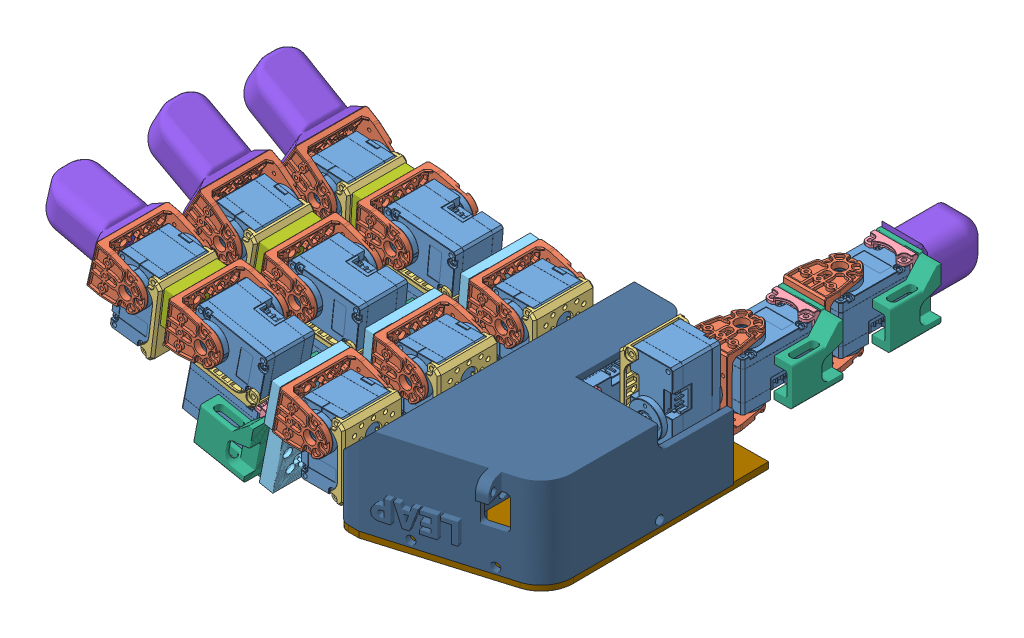
SolidWorks assembly assembly, configuration Default. Lengths in mm.
Overall size (232.03 87.75 239.65).
60 component instances, 10 part files, 172 mates.
Components (placement in the parent):
- XL,XC-330-1: XL,XC-330 [Default] at (75.5947 17.4182 -95.0965) size (20 34 29.02)
- fpx330-h101-1: fpx330-h101 [Default] at (61.8511 20.0849 -103.0965) x (-0.190479 -0.981691 0) z (0 0 -1) size (20 25 34.6)
- fpx330-s101-1: fpx330-s101 [Default] at (85.5947 9.9182 -103.0965) x (0 -1 0) z (0 0 1) size (34 7 28.6)
- fpx330-s102-1: fpx330-s102 [Default] at (42.4707 -3.1489 -103.0965) x (0 0 1) z (0.190479 0.981691 0) size (20 7 28.6)
- XL,XC-330-2: XL,XC-330 [Default] at (34.6684 6.5142 -103.0965) x (0 0 1) z (0.190479 0.981691 0) size (20 34 29.02)
- mcp_bracket-1: mcp_bracket [Default] at (58.9719 20.9961 -103.2814) x (0.190479 0.981691 0) z (0 0 1) size (53 6.5 33)
- cable_spacer-1: cable_spacer [Default] at (44.3361 -20.3094 -112.1175) x (0 0 1) z (-0.190479 -0.981691 0) size (28.5 24.1 27.99)
- fpx330-s101-2: fpx330-s101 [Default] at (29.1153 17.2689 -103.0965) x (0.981691 -0.190479 0) z (0 0 -1) size (34 7 28.6)
- XL,XC-330-3: XL,XC-330 [Default] at (23.6574 28.5144 -95.0965) x (0.190479 0.981691 0) z (0 0 1) size (20 34 29.02)
- fpx330-h101-2: fpx330-h101 [Default] at (9.7688 30.2768 -103.0965) x (-0.125885 -0.992045 0) z (0 0 -1) size (20 25 34.6)
- dip_spacer-1: dip_spacer [Default] at (1.6224 38.3666 -86.5965) x (-0.125885 -0.992045 0) z (0 0 1) size (16 6.1 25)
- XL,XC-330-4: XL,XC-330 [Default] at (-12.1554 33.0588 -95.0965) x (0.992045 -0.125885 0) z (0 0 1) size (20 34 29.02)
- fpx330-s101-3: fpx330-s101 [Default] at (-3.1791 24.3596 -103.0965) x (-0.125885 -0.992045 0) z (0 0 1) size (34 7 28.6)
- fpx330-h101-4: fpx330-h101 [Default] at (-25.8012 36.1882 -103.0965) x (-0.22353 -0.974697 0) z (0 0 -1) size (20 25 34.6)
- finger_tip-1: finger_tip [Default] at (-30.8488 27.5992 -86.5965) x (0.22353 0.974697 0) z (0 0 1) size (20.6 32.5 33)
- finger_tip-3: finger_tip [Default] at (-32.0995 30.1289 -131.9559) x (0.477322 0.878721 0.003661) z (0 -0.004166 0.999991) size (20.6 32.5 33)
- XL,XC-330-9: XL,XC-330 [Default] at (-12.6266 30.3978 -140.4549) x (0.983896 -0.17874 -0.000745) z (0 -0.004166 0.999991) size (20 34 29.02)
- dip_spacer-3: dip_spacer [Default] at (1.4153 34.9259 -131.9359) x (-0.178742 -0.983888 -0.004099) z (0 -0.004166 0.999991) size (16 6.1 25)
- fpx330-h101-8: fpx330-h101 [Default] at (-24.9288 37.1135 -148.427) x (-0.477322 -0.878721 -0.003661) z (0 0.004166 -0.999991) size (20 25 34.6)
- fpx330-s101-7: fpx330-s101 [Default] at (-4.1282 21.2645 -148.493) x (-0.178742 -0.983888 -0.004099) z (0 -0.004166 0.999991) size (34 7 28.6)
- XL,XC-330-10: XL,XC-330 [Default] at (22.8921 23.9453 -140.4818) x (0.104821 0.994482 0.004143) z (0 -0.004166 0.999991) size (20 34 29.02)
- fpx330-h101-9: fpx330-h101 [Default] at (61.6719 18.8856 -148.5029) x (-0.104821 -0.994482 -0.004143) z (0 0.004166 -0.999991) size (20 25 34.6)
- cable_spacer-3: cable_spacer [Default] at (47.7178 -22.8348 -157.6978) x (0 -0.004166 0.999991) z (-0.104821 -0.994482 -0.004143) size (28.5 24.1 27.99)
- mcp_bracket-4: mcp_bracket [Default] at (58.7247 19.545 -148.6851) x (0.104821 0.994482 0.004143) z (0 -0.004166 0.999991) size (53 6.5 33)
- XL,XC-330-11: XL,XC-330 [Default] at (35.7654 3.0139 -148.569) x (0 -0.004166 0.999991) z (0.104821 0.994482 0.004143) size (20 34 29.02)
- XL,XC-330-12: XL,XC-330 [Default] at (75.5947 17.3848 -140.5091) x (1 0 0) z (0 -0.004166 0.999991) size (20 34 29.02)
- fpx330-s102-6: fpx330-s102 [Default] at (44.3745 -5.9378 -148.6063) x (0 -0.004166 0.999991) z (0.104821 0.994482 0.004143) size (20 7 28.6)
- fpx330-s101-8: fpx330-s101 [Default] at (85.5947 9.9182 -148.5403) x (0 -0.999991 -0.004166) z (0 -0.004166 0.999991) size (34 7 28.6)
- fpx330-s101-9: fpx330-s101 [Default] at (29.3025 13.2476 -148.5264) x (0.994491 -0.10482 -0.000437) z (0 0.004166 -0.999991) size (34 7 28.6)
- fpx330-h101-10: fpx330-h101 [Default] at (9.1175 26.4809 -148.4713) x (-0.178742 -0.983888 -0.004099) z (0 0.004166 -0.999991) size (20 25 34.6)
- finger_tip-4: finger_tip [Default] at (-32.7116 25.6013 -177.4965) x (0.504165 0.863607 0) z (0 0 1) size (20.6 32.5 33)
- XL,XC-330-13: XL,XC-330 [Default] at (-13.2407 25.2347 -185.9965) x (0.998439 -0.05586 0) z (0 0 1) size (20 34 29.02)
- dip_spacer-4: dip_spacer [Default] at (0.1301 31.4976 -177.4965) x (-0.05586 -0.998439 0) z (0 0 1) size (16 6.1 25)
- fpx330-h101-11: fpx330-h101 [Default] at (-25.3312 32.293 -193.9965) x (-0.504165 -0.863607 0) z (0 0 -1) size (20 25 34.6)
- fpx330-s101-10: fpx330-s101 [Default] at (-3.6752 17.1878 -193.9965) x (-0.05586 -0.998439 0) z (0 0 1) size (34 7 28.6)
- XL,XC-330-14: XL,XC-330 [Default] at (22.803 23.2182 -185.9965) x (0.090472 0.995899 0) z (0 0 1) size (20 34 29.02)
- fpx330-h101-12: fpx330-h101 [Default] at (61.6521 18.6848 -193.9965) x (-0.090472 -0.995899 0) z (0 0 -1) size (20 25 34.6)
- cable_spacer-4: cable_spacer [Default] at (48.3016 -23.2704 -203.0175) x (0 0 1) z (-0.090472 -0.995899 0) size (28.5 24.1 27.99)
- mcp_bracket-5: mcp_bracket [Default] at (58.6958 19.3009 -194.1814) x (0.090472 0.995899 0) z (0 0 1) size (53 6.5 33)
- XL,XC-330-15: XL,XC-330 [Default] at (35.9772 2.4411 -193.9965) x (0 0 1) z (0.090472 0.995899 0) size (20 34 29.02)
- XL,XC-330-16: XL,XC-330 [Default] at (75.5947 17.4182 -185.9965) size (20 34 29.02)
- fpx330-s102-7: fpx330-s102 [Default] at (44.7145 -6.3856 -193.9965) x (0 0 1) z (0.090472 0.995899 0) size (20 7 28.6)
- fpx330-s101-11: fpx330-s101 [Default] at (85.5947 9.9182 -193.9965) x (0 -1 0) z (0 0 1) size (34 7 28.6)
- fpx330-s101-12: fpx330-s101 [Default] at (29.3675 12.5806 -193.9965) x (0.995899 -0.090472 0) z (0 0 -1) size (34 7 28.6)
- fpx330-h101-13: fpx330-h101 [Default] at (8.8248 24.0002 -193.9965) x (-0.05586 -0.998439 0) z (0 0 -1) size (20 25 34.6)
- palm_upper_no_holes-1: palm_upper_no_holes [Default] at (77.2088 -9.5217 -112.2357) x (-0.999969 -0.001716 0.007697) z (0.007698 -0.00047 0.99997) size (80 10 125)
- palm_lower-1: palm_lower [Default] at (77.3429 33.4085 -112.2687) x (-1 -0.000863 0.000028) z (0.000028 0 1) size (80.01 43 125.73)
- fpx330-s102-8: fpx330-s102 [Default] at (150.9978 20.1559 -240.0161) x (0.999999 0.000861 -0.000917) z (-0.000863 0.999996 -0.002588) size (20 7 28.6)
- cable_spacer-5: cable_spacer [Default] at (141.9863 3.644 -245.0652) x (0.999999 0.000861 -0.000917) z (0.000863 -0.999996 0.002588) size (28.5 24.1 27.99)
- finger_tip-5: finger_tip [Default] at (160.2884 3.3945 -291.6814) x (-0.999963 0.008517 0.000893) z (-0.008515 -0.99996 0.002597) size (20.6 32.5 33)
- fpx330-s102-9: fpx330-s102 [Default] at (123.5714 20.3407 -159.4912) x (-0.000863 0.999996 -0.002588) z (0.999999 0.000861 -0.000917) size (20 7 28.6)
- XL,XC-330-22: XL,XC-330 [Default] at (115.549 20.2704 -183.9838) x (-0.000863 0.999996 -0.002588) z (-0.999999 -0.000861 0.000917) size (20 34 29.02)
- fpx330-s101-16: fpx330-s101 [Default] at (141.0425 27.7923 -184.0266) x (-0.000863 0.999996 -0.002588) z (0.000915 0.002589 0.999996) size (34 7 28.6)
- XL,XC-330-23: XL,XC-330 [Default] at (151.0417 20.2802 -192.0163) x (0.999999 0.000861 -0.000917) z (-0.000915 -0.002589 -0.999996) size (20 34 29.02)
- fpx330-h101-17: fpx330-h101 [Default] at (151.033 20.2556 -201.5163) x (-0.999999 -0.000861 0.000917) z (-0.000863 0.999996 -0.002588) size (20 25 34.6)
- XL,XC-330-25: XL,XC-330 [Default] at (151.0133 28.2194 -215.5369) x (-0.999999 -0.000861 0.000917) z (-0.000863 0.999996 -0.002588) size (20 34 29.02)
- fpx330-h101-18: fpx330-h101 [Default] at (150.9904 20.135 -248.1161) x (-0.999999 -0.000861 0.000917) z (-0.000863 0.999996 -0.002588) size (20 25 34.6)
- XL,XC-330-26: XL,XC-330 [Default] at (150.9707 28.0987 -262.1368) x (-0.999999 -0.000861 0.000917) z (-0.000863 0.999996 -0.002588) size (20 34 29.02)
- fpx330-s102-12: fpx330-s102 [Default] at (150.9552 20.0353 -286.616) x (0.999999 0.000861 -0.000917) z (-0.000863 0.999996 -0.002588) size (20 7 28.6)
- cable_spacer-8: cable_spacer [Default] at (141.9437 3.5233 -291.665) x (0.999999 0.000861 -0.000917) z (0.000863 -0.999996 0.002588) size (28.5 24.1 27.99)
Mates (geometry in assembly coordinates):
- 同心12: concentric anti-aligned: cylinder of XL,XC-330-1 through (83.5947 -5.0818 -110.0965) axis (0 0 1) radius 1; circle of fpx330-s101-1
- 同心13: concentric aligned: cylinder of XL,XC-330-1 through (83.5947 24.9182 -110.0965) axis (0 0 1) radius 1; cylinder of fpx330-s101-1 through (83.5947 24.9182 -117.3965) axis (0 0 1) radius 1.025
- 重合9: coincident anti-aligned: plane of XL,XC-330-1 through (75.5947 17.4182 -114.5965) normal (0 0 -1); plane of fpx330-s101-1 through (85.5947 9.9182 -114.5965) normal (0 0 1)
- 同心23: concentric anti-aligned: cylinder of fpx330-s102-1 through (43.2311 11.2703 -95.0965) axis (0.190479 0.981691 0) radius 1.025; cylinder of XL,XC-330-2 through (42.0311 5.0856 -95.0965) axis (-0.190479 -0.981691 0) radius 1
- 重合12: coincident anti-aligned: plane of fpx330-s102-1 through (44.6612 8.1406 -103.0965) normal (-0.190479 -0.981691 0); plane of XL,XC-330-2 through (35.3351 9.9501 -103.0965) normal (0.190479 0.981691 0)
- 同心24: concentric aligned: cylinder of fpx330-s102-1 through (37.7834 -16.8061 -111.0965) axis (0.190479 0.981691 0) radius 1.025; cylinder of XL,XC-330-2 through (39.1739 -9.6398 -111.0965) axis (0.190479 0.981691 0) radius 1
- 重合15: coincident anti-aligned: plane of XL,XC-330-1 through (75.5947 17.4182 -88.5965) normal (0 0 1); plane of fpx330-h101-1 through (61.8511 20.0849 -88.5965) normal (0 0 -1)
- 同心26: concentric anti-aligned: cylinder of XL,XC-330-1 through (75.5947 17.4182 -88.5965) axis (0 0 1) radius 2.8; cylinder of fpx330-h101-1 through (75.5947 17.4182 -85.7965) axis (0 0 -1) radius 3
- 平行1: parallel anti-aligned: plane of fpx330-h101-1 through (58.906 20.6564 -103.0965) normal (-0.981691 0.190479 0); plane of mcp_bracket-1 through (51.052 -19.8214 -102.0669) normal (0.981691 -0.190479 0)
- 同心28: concentric aligned: cylinder of fpx330-h101-1 through (57.7631 14.7662 -103.0965) axis (-0.981691 0.190479 0) radius 1.025; cylinder of mcp_bracket-1 through (57.7631 14.7662 -103.0965) axis (-0.981691 0.190479 0) radius 1.2734
- 同心29: concentric anti-aligned: cylinder of fpx330-h101-1 through (60.0489 26.5465 -103.0965) axis (-0.981691 0.190479 0) radius 1.025; cylinder of mcp_bracket-1 through (58.5763 26.8322 -103.0965) axis (0.981691 -0.190479 0) radius 1.2734
- 重合17: coincident anti-aligned: plane of fpx330-h101-1 through (58.906 20.6564 -103.0965) normal (-0.981691 0.190479 0); plane of mcp_bracket-1 through (51.052 -19.8214 -102.0669) normal (0.981691 -0.190479 0)
- 同心31: concentric anti-aligned: cylinder of fpx330-s102-1 through (46.5586 2.1698 -103.0965) axis (0.981691 -0.190479 0) radius 1.025; circle of cable_spacer-1
- 同心32: concentric anti-aligned: cylinder of fpx330-s102-1 through (44.2728 -9.6105 -103.0965) axis (0.981691 -0.190479 0) radius 1.025; circle of cable_spacer-1
- 重合30: coincident anti-aligned: plane of fpx330-s102-1 through (45.4157 -3.7203 -103.0965) normal (0.981691 -0.190479 0); plane of cable_spacer-1 through (47.8473 8.8114 -104.0783) normal (-0.981691 0.190479 0)
- 同心33: concentric aligned: circle of mcp_bracket-1; circle of cable_spacer-1
- 同心34: concentric aligned: circle of mcp_bracket-1; circle of cable_spacer-1
- 重合35: coincident anti-aligned: plane of mcp_bracket-1 through (47.1511 -5.8015 -112.2192) normal (-0.981691 0.190479 0); plane of cable_spacer-1 through (49.9088 8.4114 -102.1568) normal (0.981691 -0.190479 0)
- 同心35: concentric aligned: cylinder of fpx330-s101-2 through (44.2216 16.3751 -88.7965) axis (0 0 -1) radius 1.025; cylinder of XL,XC-330-3 through (44.2216 16.3751 -95.0965) axis (0 0 -1) radius 1
- 同心36: concentric aligned: circle of fpx330-s101-2; cylinder of XL,XC-330-3 through (14.7709 22.0894 -95.0965) axis (0 0 -1) radius 1
- 重合36: coincident anti-aligned: plane of fpx330-s101-2 through (29.1153 17.2689 -91.5965) normal (0 0 -1); plane of XL,XC-330-3 through (23.6574 28.5144 -91.5965) normal (0 0 1)
- 同心38: concentric anti-aligned: cylinder of XL,XC-330-3 through (23.6574 28.5144 -88.5965) axis (0 0 1) radius 2.8; cylinder of fpx330-h101-2 through (23.6574 28.5144 -85.7965) axis (0 0 -1) radius 3
- 重合38: coincident anti-aligned: plane of XL,XC-330-3 through (23.6574 28.5144 -88.5965) normal (0 0 1); plane of fpx330-h101-2 through (9.7688 30.2768 -88.5965) normal (0 0 -1)
- 同心40: concentric anti-aligned: cylinder of fpx330-h101-2 through (6.7926 30.6544 -109.0965) axis (-0.992045 0.125885 0) radius 1.025; circle of dip_spacer-1
- 同心41: concentric anti-aligned: cylinder of fpx330-h101-2 through (6.7926 30.6544 -97.0965) axis (-0.992045 0.125885 0) radius 1.025; circle of dip_spacer-1
- 重合40: coincident anti-aligned: plane of fpx330-h101-2 through (6.7926 30.6544 -103.0965) normal (-0.992045 0.125885 0); plane of dip_spacer-1 through (5.9978 24.3905 -110.5314) normal (0.992045 -0.125885 0)
- 同心42: concentric anti-aligned: cylinder of XL,XC-330-4 through (-7.0515 9.7307 -95.0965) axis (0 0 -1) radius 1; cylinder of fpx330-s101-3 through (-7.0515 9.7307 -88.7965) axis (0 0 1) radius 1.025
- 同心43: concentric anti-aligned: cylinder of XL,XC-330-4 through (-3.2749 39.4921 -95.0965) axis (0 0 -1) radius 1; cylinder of fpx330-s101-3 through (-3.2749 39.4921 -88.7965) axis (0 0 1) radius 1.025
- 重合41: coincident anti-aligned: plane of XL,XC-330-4 through (-12.1554 33.0588 -114.5965) normal (0 0 -1); plane of fpx330-s101-3 through (-3.1791 24.3596 -114.5965) normal (0 0 1)
- 同心44: concentric anti-aligned: circle of dip_spacer-1; circle of fpx330-s101-3
- 同心45: concentric aligned: circle of dip_spacer-1; cylinder of fpx330-s101-3 through (0.7412 31.4223 -97.0965) axis (0.992045 -0.125885 0) radius 1.025
- 重合42: coincident anti-aligned: plane of dip_spacer-1 through (-0.0537 25.1584 -95.6617) normal (-0.992045 0.125885 0); plane of fpx330-s101-3 through (-0.203 23.982 -103.0965) normal (0.992045 -0.125885 0)
- 重合48: coincident anti-aligned: plane of XL,XC-330-4 through (-12.1554 33.0588 -88.5965) normal (0 0 1); plane of fpx330-h101-4 through (-25.8012 36.1882 -88.5965) normal (0 0 -1)
- 同心47: concentric anti-aligned: circle of XL,XC-330-4; cylinder of fpx330-h101-4 through (-12.1554 33.0588 -85.7965) axis (0 0 -1) radius 3
- 同心48: concentric aligned: circle of fpx330-h101-4; circle of finger_tip-1
- 同心49: concentric aligned: circle of fpx330-h101-4; circle of finger_tip-1
- 重合49: coincident anti-aligned: plane of fpx330-h101-4 through (-28.7253 36.8588 -103.0965) normal (-0.974697 0.22353 0); plane of finger_tip-1 through (-30.32 29.9052 -112.0355) normal (0.974697 -0.22353 0)
- 同心50: concentric anti-aligned: circle of XL,XC-330-2; circle of fpx330-s101-2
- 同心51: concentric anti-aligned: circle of XL,XC-330-2; circle of fpx330-s101-2
- 重合50: coincident anti-aligned: plane of XL,XC-330-2 through (35.9065 12.8952 -103.0965) normal (0.190479 0.981691 0); plane of fpx330-s101-2 through (28.5439 14.3238 -103.0965) normal (-0.190479 -0.981691 0)
- 重合65: coincident anti-aligned: plane of XL,XC-330-9 through (-12.6266 30.479 -159.9547) normal (0 0.004166 -0.999991); plane of fpx330-s101-7 through (-4.1282 21.3125 -159.9929) normal (0 -0.004166 0.999991)
- 重合66: coincident anti-aligned: plane of cable_spacer-3 through (50.7845 6.2188 -147.6159) normal (0.994491 -0.10482 -0.000437); plane of mcp_bracket-4 through (49.2669 -8.1374 -157.7383) normal (-0.994491 0.10482 0.000437)
- 重合67: coincident anti-aligned: plane of XL,XC-330-10 through (22.8921 23.9182 -133.9818) normal (0 -0.004166 0.999991); plane of fpx330-h101-10 through (9.1175 26.4205 -133.9714) normal (0 0.004166 -0.999991)
- 重合68: coincident anti-aligned: plane of cable_spacer-3 through (48.6961 6.4469 -149.5366) normal (-0.994491 0.10482 0.000437); plane of fpx330-s102-6 through (47.358 -6.2522 -148.6077) normal (0.994491 -0.10482 -0.000437)
- 重合69: coincident anti-aligned: plane of dip_spacer-3 through (-0.9645 21.8641 -141.0556) normal (-0.983896 0.17874 0.000745); plane of fpx330-s101-7 through (-1.1765 20.7283 -148.4952) normal (0.983896 -0.17874 -0.000745)
- 重合70: coincident anti-aligned: plane of XL,XC-330-11 through (36.1323 6.4946 -148.5545) normal (0.104821 0.994482 0.004143); plane of fpx330-s102-6 through (45.58 5.4988 -148.5587) normal (-0.104821 -0.994482 -0.004143)
- 平行15: parallel anti-aligned: plane of fpx330-h101-9 through (58.6884 19.2001 -148.5016) normal (-0.994491 0.10482 0.000437); plane of mcp_bracket-4 through (54.3663 -21.8094 -147.6428) normal (0.994491 -0.10482 -0.000437)
- 重合71: coincident anti-aligned: plane of fpx330-h101-9 through (58.6884 19.2001 -148.5016) normal (-0.994491 0.10482 0.000437); plane of mcp_bracket-4 through (54.3663 -21.8094 -147.6428) normal (0.994491 -0.10482 -0.000437)
- 重合72: coincident anti-aligned: plane of XL,XC-330-12 through (75.5947 17.4661 -160.0089) normal (0 0.004166 -0.999991); plane of fpx330-s101-8 through (85.5947 9.9661 -160.0402) normal (0 -0.004166 0.999991)
- 重合73: coincident anti-aligned: plane of fpx330-h101-9 through (61.6719 18.8252 -134.003) normal (0 0.004166 -0.999991); plane of XL,XC-330-12 through (75.5947 17.3577 -134.0092) normal (0 -0.004166 0.999991)
- 同心77: concentric anti-aligned: cylinder of XL,XC-330-12 through (83.5947 -5.0525 -155.6027) axis (0 -0.004166 0.999991) radius 1; circle of fpx330-s101-8
- 同心78: concentric anti-aligned: cylinder of fpx330-h101-9 through (59.3173 25.167 -148.4767) axis (-0.994491 0.10482 0.000437) radius 1.025; cylinder of mcp_bracket-4 through (57.8256 25.3242 -148.4761) axis (0.994491 -0.10482 -0.000437) radius 1.2734
- 同心79: concentric aligned: cylinder of fpx330-h101-9 through (58.0595 13.2332 -148.5265) axis (-0.994491 0.10482 0.000437) radius 1.025; cylinder of mcp_bracket-4 through (58.0595 13.2332 -148.5265) axis (-0.994491 0.10482 0.000437) radius 1.2734
- 同心80: concentric anti-aligned: cylinder of XL,XC-330-11 through (43.2241 2.1944 -140.5724) axis (-0.104821 -0.994482 -0.004143) radius 1; cylinder of fpx330-s102-6 through (43.8845 8.4596 -140.5463) axis (0.104821 0.994482 0.004143) radius 1.025
- 同心81: concentric aligned: cylinder of XL,XC-330-11 through (41.6518 -12.6562 -156.6344) axis (0.104821 0.994482 0.004143) radius 1; cylinder of fpx330-s102-6 through (40.8866 -19.9159 -156.6646) axis (0.104821 0.994482 0.004143) radius 1.025
- 同心82: concentric anti-aligned: cylinder of fpx330-h101-9 through (75.5947 17.3461 -131.2092) axis (0 0.004166 -0.999991) radius 3; cylinder of XL,XC-330-12 through (75.5947 17.3577 -134.0092) axis (0 -0.004166 0.999991) radius 2.8
- 同心83: concentric aligned: cylinder of XL,XC-330-12 through (83.5947 24.9472 -155.4777) axis (0 -0.004166 0.999991) radius 1; cylinder of fpx330-s101-8 through (83.5947 24.9777 -162.7777) axis (0 -0.004166 0.999991) radius 1.025
- 重合74: coincident anti-aligned: plane of XL,XC-330-10 through (22.8921 23.9307 -136.9818) normal (0 -0.004166 0.999991); plane of fpx330-s101-9 through (29.3025 13.1997 -137.0265) normal (0 0.004166 -0.999991)
- 重合75: coincident anti-aligned: plane of dip_spacer-3 through (5.0372 20.8358 -155.9297) normal (0.983896 -0.17874 -0.000745); plane of fpx330-h101-10 through (6.1658 27.0172 -148.469) normal (-0.983896 0.17874 0.000745)
- 同心84: concentric anti-aligned: cylinder of XL,XC-330-10 through (22.8921 23.9182 -133.9818) axis (0 -0.004166 0.999991) radius 2.8; cylinder of fpx330-h101-10 through (22.8921 23.9065 -131.1818) axis (0 0.004166 -0.999991) radius 3
- 同心85: concentric anti-aligned: circle of dip_spacer-3; circle of fpx330-s101-7
- 同心86: concentric anti-aligned: circle of dip_spacer-3; cylinder of fpx330-h101-10 through (6.1658 27.0422 -154.469) axis (-0.983896 0.17874 0.000745) radius 1.025
- 同心87: concentric aligned: cylinder of XL,XC-330-10 through (44.4296 13.6309 -140.5247) axis (0 0.004166 -0.999991) radius 1; cylinder of fpx330-s101-9 through (44.4296 13.6047 -134.2248) axis (0 0.004166 -0.999991) radius 1.025
- 同心88: concentric aligned: cylinder of XL,XC-330-10 through (14.5948 16.7755 -140.5116) axis (0 0.004166 -0.999991) radius 1; circle of fpx330-s101-9
- 同心89: concentric anti-aligned: circle of dip_spacer-3; cylinder of fpx330-h101-10 through (6.1658 26.9922 -142.4691) axis (-0.983896 0.17874 0.000745) radius 1.025
- 同心90: concentric anti-aligned: cylinder of XL,XC-330-9 through (-8.7771 6.8304 -140.5531) axis (0 0.004166 -0.999991) radius 1; cylinder of fpx330-s101-7 through (-8.7771 6.8041 -134.2531) axis (0 -0.004166 0.999991) radius 1.025
- 同心91: concentric anti-aligned: cylinder of XL,XC-330-9 through (-3.4148 36.347 -140.4301) axis (0 0.004166 -0.999991) radius 1; cylinder of fpx330-s101-7 through (-3.4148 36.3208 -134.1302) axis (0 -0.004166 0.999991) radius 1.025
- 同心92: concentric aligned: circle of dip_spacer-3; cylinder of fpx330-s101-7 through (0.1641 28.0825 -142.4645) axis (0.983896 -0.17874 -0.000745) radius 1.025
- 同心93: concentric anti-aligned: circle of XL,XC-330-9; cylinder of fpx330-h101-8 through (-12.6266 30.359 -131.155) axis (0 0.004166 -0.999991) radius 3
- 同心94: concentric aligned: circle of cable_spacer-3; circle of mcp_bracket-4
- 同心95: concentric aligned: circle of cable_spacer-3; circle of mcp_bracket-4
- 同心96: concentric anti-aligned: circle of cable_spacer-3; cylinder of fpx330-s102-6 through (46.7291 -12.2191 -148.6325) axis (0.994491 -0.10482 -0.000437) radius 1.025
- 同心97: concentric anti-aligned: circle of cable_spacer-3; cylinder of fpx330-s102-6 through (47.9869 -0.2853 -148.5828) axis (0.994491 -0.10482 -0.000437) radius 1.025
- 重合76: coincident anti-aligned: plane of XL,XC-330-9 through (-12.6266 30.3707 -133.9549) normal (0 -0.004166 0.999991); plane of fpx330-h101-8 through (-24.9288 37.0531 -133.9271) normal (0 0.004166 -0.999991)
- 重合77: coincident anti-aligned: plane of finger_tip-3 through (-30.9702 32.3138 -157.386) normal (0.878729 -0.477317 -0.001989); plane of fpx330-h101-8 through (-27.565 38.5455 -148.421) normal (-0.878729 0.477317 0.001989)
- 同心98: concentric anti-aligned: circle of XL,XC-330-11; circle of fpx330-s101-9
- 同心99: concentric aligned: circle of finger_tip-3; circle of fpx330-h101-8
- 同心100: concentric anti-aligned: circle of XL,XC-330-11; circle of fpx330-s101-9
- 同心101: concentric aligned: circle of finger_tip-3; circle of fpx330-h101-8
- 重合78: coincident anti-aligned: plane of XL,XC-330-11 through (36.4468 9.478 -148.5421) normal (0.104821 0.994482 0.004143); plane of fpx330-s101-9 through (28.9881 10.2642 -148.5388) normal (-0.104821 -0.994482 -0.004143)
- 重合79: coincident anti-aligned: plane of XL,XC-330-13 through (-13.2407 25.2347 -205.4965) normal (0 0 -1); plane of fpx330-s101-10 through (-3.6752 17.1878 -205.4965) normal (0 0 1)
- 重合80: coincident anti-aligned: plane of cable_spacer-4 through (50.9485 5.8661 -193.0568) normal (0.995899 -0.090472 0); plane of mcp_bracket-5 through (49.6387 -8.5525 -203.1192) normal (-0.995899 0.090472 0)
- 重合81: coincident anti-aligned: plane of XL,XC-330-14 through (22.803 23.2182 -179.4965) normal (0 0 1); plane of fpx330-h101-13 through (8.8248 24.0002 -179.4965) normal (0 0 -1)
- 重合82: coincident anti-aligned: plane of cable_spacer-4 through (48.8571 6.0561 -194.9783) normal (-0.995899 0.090472 0); plane of fpx330-s102-7 through (47.7022 -6.657 -193.9965) normal (0.995899 -0.090472 0)
- 重合83: coincident anti-aligned: plane of dip_spacer-4 through (-0.6137 18.2043 -186.5617) normal (-0.998439 0.05586 0); plane of fpx330-s101-10 through (-0.6799 17.0202 -193.9965) normal (0.998439 -0.05586 0)
- 重合84: coincident anti-aligned: plane of XL,XC-330-15 through (36.2939 5.9267 -193.9965) normal (0.090472 0.995899 0); plane of fpx330-s102-7 through (45.7549 5.0672 -193.9965) normal (-0.090472 -0.995899 0)
- 平行16: parallel anti-aligned: plane of fpx330-h101-12 through (58.6644 18.9562 -193.9965) normal (-0.995899 0.090472 0); plane of mcp_bracket-5 through (54.9341 -22.1074 -192.9669) normal (0.995899 -0.090472 0)
- 重合85: coincident anti-aligned: plane of fpx330-h101-12 through (58.6644 18.9562 -193.9965) normal (-0.995899 0.090472 0); plane of mcp_bracket-5 through (54.9341 -22.1074 -192.9669) normal (0.995899 -0.090472 0)
- 重合86: coincident anti-aligned: plane of XL,XC-330-16 through (75.5947 17.4182 -205.4965) normal (0 0 -1); plane of fpx330-s101-11 through (85.5947 9.9182 -205.4965) normal (0 0 1)
- 重合87: coincident anti-aligned: plane of fpx330-h101-12 through (61.6521 18.6848 -179.4965) normal (0 0 -1); plane of XL,XC-330-16 through (75.5947 17.4182 -179.4965) normal (0 0 1)
- 同心102: concentric anti-aligned: cylinder of XL,XC-330-16 through (83.5947 -5.0818 -200.9965) axis (0 0 1) radius 1; circle of fpx330-s101-11
- 同心103: concentric anti-aligned: cylinder of fpx330-h101-12 through (59.2073 24.9316 -193.9965) axis (-0.995899 0.090472 0) radius 1.025; cylinder of mcp_bracket-5 through (57.7134 25.0673 -193.9965) axis (0.995899 -0.090472 0) radius 1.2734
- 同心104: concentric aligned: cylinder of fpx330-h101-12 through (58.1216 12.9808 -193.9965) axis (-0.995899 0.090472 0) radius 1.025; cylinder of mcp_bracket-5 through (58.1216 12.9808 -193.9965) axis (-0.995899 0.090472 0) radius 1.2734
- 同心105: concentric anti-aligned: cylinder of XL,XC-330-15 through (43.4465 1.7625 -185.9965) axis (-0.090472 -0.995899 0) radius 1; cylinder of fpx330-s102-7 through (44.0165 8.0367 -185.9965) axis (0.090472 0.995899 0) radius 1.025
- 同心106: concentric aligned: cylinder of XL,XC-330-15 through (42.0894 -13.176 -201.9965) axis (0.090472 0.995899 0) radius 1; cylinder of fpx330-s102-7 through (41.429 -20.446 -201.9965) axis (0.090472 0.995899 0) radius 1.025
- 同心107: concentric anti-aligned: cylinder of fpx330-h101-12 through (75.5947 17.4182 -176.6965) axis (0 0 -1) radius 3; cylinder of XL,XC-330-16 through (75.5947 17.4182 -179.4965) axis (0 0 1) radius 2.8
- 同心108: concentric aligned: cylinder of XL,XC-330-16 through (83.5947 24.9182 -200.9965) axis (0 0 1) radius 1; cylinder of fpx330-s101-11 through (83.5947 24.9182 -208.2965) axis (0 0 1) radius 1.025
- 重合88: coincident anti-aligned: plane of XL,XC-330-14 through (22.803 23.2182 -182.4965) normal (0 0 1); plane of fpx330-s101-12 through (29.3675 12.5806 -182.4965) normal (0 0 -1)
- 重合89: coincident anti-aligned: plane of dip_spacer-4 through (5.4768 17.8635 -201.4314) normal (0.998439 -0.05586 0); plane of fpx330-h101-13 through (5.8295 24.1678 -193.9965) normal (-0.998439 0.05586 0)
- 同心109: concentric anti-aligned: cylinder of XL,XC-330-14 through (22.803 23.2182 -179.4965) axis (0 0 1) radius 2.8; cylinder of fpx330-h101-13 through (22.803 23.2182 -176.6965) axis (0 0 -1) radius 3
- 同心110: concentric anti-aligned: circle of dip_spacer-4; circle of fpx330-s101-10
- 同心111: concentric anti-aligned: circle of dip_spacer-4; cylinder of fpx330-h101-13 through (5.8295 24.1678 -199.9965) axis (-0.998439 0.05586 0) radius 1.025
- 同心112: concentric aligned: cylinder of XL,XC-330-14 through (44.4869 13.2154 -185.9965) axis (0 0 -1) radius 1; cylinder of fpx330-s101-12 through (44.4869 13.2154 -179.6965) axis (0 0 -1) radius 1.025
- 同心113: concentric aligned: cylinder of XL,XC-330-14 through (14.6099 15.9295 -185.9965) axis (0 0 -1) radius 1; circle of fpx330-s101-12
- 同心114: concentric anti-aligned: circle of dip_spacer-4; cylinder of fpx330-h101-13 through (5.8295 24.1678 -187.9965) axis (-0.998439 0.05586 0) radius 1.025
- 同心115: concentric anti-aligned: cylinder of XL,XC-330-13 through (-6.51 2.323 -185.9965) axis (0 0 -1) radius 1; cylinder of fpx330-s101-10 through (-6.51 2.323 -179.6965) axis (0 0 1) radius 1.025
- 同心116: concentric anti-aligned: cylinder of XL,XC-330-13 through (-4.8342 32.2761 -185.9965) axis (0 0 -1) radius 1; cylinder of fpx330-s101-10 through (-4.8342 32.2761 -179.6965) axis (0 0 1) radius 1.025
- 同心117: concentric aligned: circle of dip_spacer-4; cylinder of fpx330-s101-10 through (-0.261 24.5085 -187.9965) axis (0.998439 -0.05586 0) radius 1.025
- 同心118: concentric anti-aligned: circle of XL,XC-330-13; cylinder of fpx330-h101-11 through (-13.2407 25.2347 -176.6965) axis (0 0 -1) radius 3
- 同心119: concentric aligned: circle of cable_spacer-4; circle of mcp_bracket-5
- 同心120: concentric aligned: circle of cable_spacer-4; circle of mcp_bracket-5
- 同心121: concentric anti-aligned: circle of cable_spacer-4; cylinder of fpx330-s102-7 through (47.1594 -12.6324 -193.9965) axis (0.995899 -0.090472 0) radius 1.025
- 同心122: concentric anti-aligned: circle of cable_spacer-4; cylinder of fpx330-s102-7 through (48.245 -0.6816 -193.9965) axis (0.995899 -0.090472 0) radius 1.025
- 重合90: coincident anti-aligned: plane of XL,XC-330-13 through (-13.2407 25.2347 -179.4965) normal (0 0 1); plane of fpx330-h101-11 through (-25.3312 32.293 -179.4965) normal (0 0 -1)
- 重合91: coincident anti-aligned: plane of finger_tip-4 through (-31.5188 27.6444 -202.9355) normal (0.863607 -0.504165 0); plane of fpx330-h101-11 through (-27.922 33.8055 -193.9965) normal (-0.863607 0.504165 0)
- 同心123: concentric anti-aligned: circle of XL,XC-330-15; circle of fpx330-s101-12
- 同心124: concentric aligned: circle of finger_tip-4; circle of fpx330-h101-11
- 同心125: concentric anti-aligned: circle of XL,XC-330-15; circle of fpx330-s101-12
- 同心126: concentric aligned: circle of finger_tip-4; circle of fpx330-h101-11
- 重合92: coincident anti-aligned: plane of XL,XC-330-15 through (36.5653 8.9144 -193.9965) normal (0.090472 0.995899 0); plane of fpx330-s101-12 through (29.0961 9.5929 -193.9965) normal (-0.090472 -0.995899 0)
- 同心127: concentric aligned: circle of fpx330-s101-1; circle of palm_lower-1
- 同心128: concentric aligned: circle of fpx330-s101-1; circle of palm_lower-1
- 重合94: coincident anti-aligned: plane of fpx330-s101-1 through (88.5947 9.9182 -103.0965) normal (1 0 0); plane of palm_lower-1 through (88.5947 9.8601 -96.4321) normal (-1 0 0)
- 同心129: concentric aligned: cylinder of fpx330-s101-8 through (88.5947 -3.5817 -148.5965) axis (-1 0 0) radius 1.025; circle of palm_lower-1
- 同心130: concentric aligned: circle of fpx330-s101-8; circle of palm_lower-1
- 重合96: coincident anti-aligned: plane of fpx330-s101-8 through (88.5947 9.9182 -148.5403) normal (1 0 0); plane of palm_lower-1 through (88.5947 9.8601 -96.4321) normal (-1 0 0)
- 同心131: concentric aligned: circle of fpx330-s101-11; circle of palm_lower-1
- 同心132: concentric aligned: circle of fpx330-s101-11; circle of palm_lower-1
- 重合101: coincident anti-aligned: plane of fpx330-s101-11 through (88.5947 9.9182 -193.9965) normal (1 0 0); plane of palm_lower-1 through (88.5947 9.8601 -96.4321) normal (-1 0 0)
- 重合107: coincident anti-aligned: plane of fpx330-s102-8 through (150.995 20.1482 -243.0161) normal (-0.000915 -0.002589 -0.999996); plane of cable_spacer-5 through (150.0022 32.9127 -243.0483) normal (0.000915 0.002589 0.999996)
- 同心139: concentric anti-aligned: cylinder of fpx330-s102-8 through (151.0002 14.1482 -243.0006) axis (-0.000915 -0.002589 -0.999996) radius 1.025; circle of cable_spacer-5
- 同心141: concentric anti-aligned: cylinder of fpx330-s102-8 through (150.9899 26.1482 -243.0317) axis (-0.000915 -0.002589 -0.999996) radius 1.025; circle of cable_spacer-5
- 同心158: concentric anti-aligned: cylinder of fpx330-s102-9 through (109.2765 12.3232 -161.4574) axis (0.999999 0.000861 -0.000917) radius 1.025; cylinder of XL,XC-330-22 through (130.5765 12.3416 -161.4769) axis (-0.999999 -0.000861 0.000917) radius 1
- 同心159: concentric anti-aligned: circle of fpx330-s102-9; cylinder of XL,XC-330-22 through (130.5627 28.3415 -161.5184) axis (-0.999999 -0.000861 0.000917) radius 1
- 平行18: parallel anti-aligned: plane of fpx330-s102-9 through (123.5714 20.3407 -159.4912) normal (-0.000915 -0.002589 -0.999996); plane of XL,XC-330-22 through (115.5801 10.3338 -159.458) normal (0.000915 0.002589 0.999996)
- 重合119: coincident anti-aligned: plane of fpx330-s102-9 through (112.0714 20.3308 -159.4807) normal (0.999999 0.000861 -0.000917); plane of XL,XC-330-22 through (112.049 20.2674 -183.9806) normal (-0.999999 -0.000861 0.000917)
- 同心162: concentric anti-aligned: cylinder of fpx330-s101-16 through (143.0165 42.7569 -198.3672) axis (0.000915 0.002589 0.999996) radius 1.025; cylinder of XL,XC-330-23 through (143.036 42.8121 -177.0673) axis (-0.000915 -0.002589 -0.999996) radius 1
- 重合123: coincident anti-aligned: plane of fpx330-s101-16 through (141.0425 27.7923 -184.0266) normal (0.999999 0.000861 -0.000917); plane of XL,XC-330-23 through (141.0499 10.7717 -191.9826) normal (-0.999999 -0.000861 0.000917)
- 重合124: coincident anti-aligned: plane of fpx330-s101-16 through (141.032 27.7625 -195.5266) normal (0.000915 0.002589 0.999996); plane of XL,XC-330-23 through (151.0385 20.2712 -195.5163) normal (-0.000915 -0.002589 -0.999996)
- 同心164: concentric anti-aligned: cylinder of XL,XC-330-22 through (138.0542 14.2898 -183.9889) axis (0.999999 0.000861 -0.000917) radius 0.8; cylinder of fpx330-s101-16 through (138.0542 14.2898 -183.9889) axis (-0.999999 -0.000861 0.000917) radius 1.025
- 同心165: concentric anti-aligned: cylinder of XL,XC-330-22 through (138.0438 26.2897 -184.02) axis (0.999999 0.000861 -0.000917) radius 0.8; cylinder of fpx330-s101-16 through (138.0438 26.2897 -184.02) axis (-0.999999 -0.000861 0.000917) radius 1.025
- 重合125: coincident anti-aligned: plane of XL,XC-330-22 through (138.049 20.2897 -184.0044) normal (0.999999 0.000861 -0.000917); plane of fpx330-s101-16 through (138.0425 27.7897 -184.0238) normal (-0.999999 -0.000861 0.000917)
- 同心166: concentric aligned: circle of XL,XC-330-23; cylinder of fpx330-h101-17 through (151.0409 14.2634 -198.5008) axis (0.000915 0.002589 0.999996) radius 1.025
- 同心167: concentric aligned: cylinder of XL,XC-330-23 through (151.0306 26.2634 -198.5318) axis (0.000915 0.002589 0.999996) radius 0.8; cylinder of fpx330-h101-17 through (151.0306 26.2634 -198.5318) axis (0.000915 0.002589 0.999996) radius 1.025
- 重合126: coincident anti-aligned: plane of XL,XC-330-23 through (151.0357 20.2634 -198.5163) normal (-0.000915 -0.002589 -0.999996); plane of fpx330-h101-17 through (151.0357 20.2634 -198.5163) normal (0.000915 0.002589 0.999996)
- 同心178: concentric anti-aligned: cylinder of fpx330-h101-17 through (145.0053 37.5141 -215.5555) axis (-0.000863 0.999996 -0.002588) radius 1.025; circle of XL,XC-330-25
- 同心179: concentric anti-aligned: cylinder of fpx330-h101-17 through (157.0351 2.9246 -215.477) axis (-0.000863 0.999996 -0.002588) radius 1.025; cylinder of XL,XC-330-25 through (157.0077 34.7245 -215.5593) axis (0.000863 -0.999996 0.002588) radius 0.8
- 重合133: coincident anti-aligned: plane of fpx330-h101-17 through (151.0205 34.7556 -201.5538) normal (0.000863 -0.999996 0.002588); plane of XL,XC-330-25 through (151.0077 34.7193 -215.5538) normal (-0.000863 0.999996 -0.002588)
- 同心180: concentric aligned: cylinder of fpx330-s102-8 through (143.012 5.8543 -237.9718) axis (-0.000863 0.999996 -0.002588) radius 1.025; circle of XL,XC-330-25
- 同心181: concentric anti-aligned: cylinder of fpx330-s102-8 through (158.9873 34.468 -238.0605) axis (-0.000863 0.999996 -0.002588) radius 1.025; circle of XL,XC-330-25
- 重合134: coincident anti-aligned: plane of fpx330-s102-8 through (150.9879 31.6559 -240.0459) normal (0.000863 -0.999996 0.002588); plane of XL,XC-330-25 through (151.0103 31.7193 -215.546) normal (-0.000863 0.999996 -0.002588)
- 同心182: concentric anti-aligned: cylinder of fpx330-s102-12 through (150.9576 14.0275 -289.6004) axis (-0.000915 -0.002589 -0.999996) radius 1.025; circle of cable_spacer-8
- 同心183: concentric anti-aligned: cylinder of fpx330-s102-12 through (150.9472 26.0275 -289.6315) axis (-0.000915 -0.002589 -0.999996) radius 1.025; circle of cable_spacer-8
- 同心184: concentric anti-aligned: cylinder of fpx330-h101-18 through (144.9626 37.3935 -262.1553) axis (-0.000863 0.999996 -0.002588) radius 1.025; circle of XL,XC-330-26
- 重合135: coincident anti-aligned: plane of fpx330-s102-12 through (150.9524 20.0275 -289.616) normal (-0.000915 -0.002589 -0.999996); plane of cable_spacer-8 through (149.9596 32.7921 -289.6481) normal (0.000915 0.002589 0.999996)
- 重合136: coincident anti-aligned: plane of fpx330-h101-18 through (150.9779 34.6349 -248.1536) normal (0.000863 -0.999996 0.002588); plane of XL,XC-330-26 through (150.965 34.5987 -262.1536) normal (-0.000863 0.999996 -0.002588)
- 重合137: coincident anti-aligned: plane of XL,XC-330-26 through (150.9676 31.5987 -262.1458) normal (-0.000863 0.999996 -0.002588); plane of fpx330-s102-12 through (150.9452 31.5352 -286.6457) normal (0.000863 -0.999996 0.002588)
- 同心185: concentric anti-aligned: cylinder of fpx330-h101-18 through (156.9925 2.804 -262.0768) axis (-0.000863 0.999996 -0.002588) radius 1.025; cylinder of XL,XC-330-26 through (156.965 34.6038 -262.1591) axis (0.000863 -0.999996 0.002588) radius 0.8
- 同心186: concentric anti-aligned: circle of XL,XC-330-26; cylinder of fpx330-s102-12 through (158.9446 34.3473 -284.6603) axis (-0.000863 0.999996 -0.002588) radius 1.025
- 同心187: concentric aligned: circle of XL,XC-330-26; cylinder of fpx330-s102-12 through (142.9693 5.7336 -284.5716) axis (-0.000863 0.999996 -0.002588) radius 1.025
- 同心189: concentric anti-aligned: circle of fpx330-s102-8; cylinder of fpx330-h101-18 through (150.9983 14.1428 -245.1006) axis (0.000915 0.002589 0.999996) radius 1.025
- 同心191: concentric anti-aligned: cylinder of fpx330-s102-8 through (150.9899 26.1482 -243.0317) axis (-0.000915 -0.002589 -0.999996) radius 1.025; cylinder of fpx330-h101-18 through (150.9879 26.1427 -245.1317) axis (0.000915 0.002589 0.999996) radius 1.025
- 重合142: coincident anti-aligned: plane of cable_spacer-5 through (151.9219 32.909 -245.15) normal (-0.000915 -0.002589 -0.999996); plane of fpx330-h101-18 through (150.9931 20.1427 -245.1161) normal (0.000915 0.002589 0.999996)
- 同心192: concentric aligned: circle of finger_tip-5; circle of cable_spacer-8
- 同心193: concentric aligned: circle of finger_tip-5; circle of cable_spacer-8
- 重合143: coincident anti-aligned: plane of finger_tip-5 through (158.1392 28.8526 -291.7454) normal (0.000915 0.002589 0.999996); plane of cable_spacer-8 through (151.8792 32.7883 -291.7499) normal (-0.000915 -0.002589 -0.999996)
- 同心194: concentric anti-aligned: circle of palm_lower-1; cylinder of fpx330-s102-9 through (123.569 26.3484 -156.5068) axis (0.000915 0.002589 0.999996) radius 1.025
- 同心195: concentric anti-aligned: circle of palm_lower-1; cylinder of fpx330-s102-9 through (123.5794 14.3485 -156.4757) axis (0.000915 0.002589 0.999996) radius 1.025
- 重合145: coincident anti-aligned: plane of palm_lower-1 through (131.6028 27.3595 -156.5167) normal (-0.000915 -0.002589 -0.999996); plane of fpx330-s102-9 through (123.5742 20.3485 -156.4912) normal (0.000915 0.002589 0.999996)
- 同心196: concentric anti-aligned: cylinder of palm_upper_no_holes-1 through (97.1068 -12.4984 -89.9982) axis (-0.001712 0.999998 0.000483) radius 2.1; circle of palm_lower-1
- 重合146: coincident anti-aligned: plane of palm_upper_no_holes-1 through (128.1495 -9.4168 -148.8564) normal (-0.001712 0.999998 0.000483); plane of palm_lower-1 through (167.5997 -9.3466 -154.5067) normal (0.001712 -0.999998 -0.000483)
- 同心201: concentric aligned: circle of palm_upper_no_holes-1; circle of palm_lower-1
